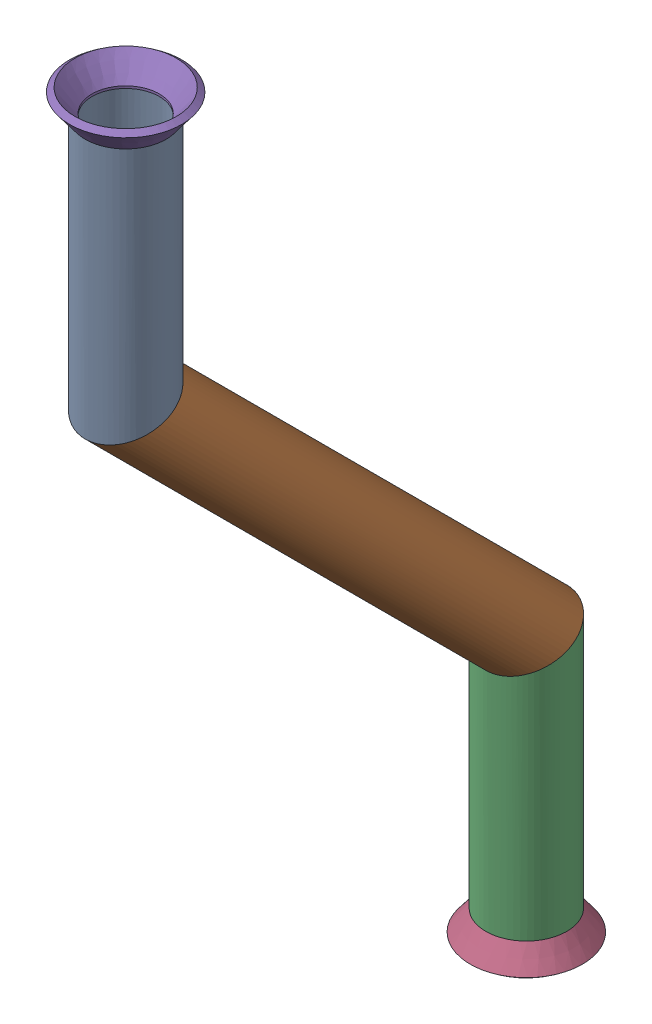
SolidWorks assembly pipe 53, configuration Default. Lengths in mm.
Overall size (17.59 146.84 80.46).
3 component instances, 2 part files, 4 mates.
Components (placement in the parent):
- Part2-1: Part2 [Default<As Machined>] at origin size (12.7 139.06 75.56)
- Flared pipe end - .5 inch-1: Flared pipe end - .5 inch [Default<As Machined>] at (0 -189.578 244.7365) x (1 0 -0.00017) z (0 -1 0) size (17.59 17.59 3.89)
- Flared pipe end - .5 inch-2: Flared pipe end - .5 inch [Default<As Machined>] at (0 -50.5162 307.5983) x (1 0 0.00017) z (0 1 0) size (17.59 17.59 3.89)
Mates (geometry in assembly coordinates):
- Coincident1029: coincident: plane of Part2-1 through (0 -189.578 244.7365) normal (0 -1 0); plane of Flared pipe end - .5 inch-1 through (0.0009 -189.578 250.0197) normal (0 1 0)
- Concentric657: concentric: circle of Part2-1; circle of Flared pipe end - .5 inch-1
- Coincident1027: coincident: plane of Part2-1 through (0 -50.5162 307.5983) normal (0 1 0); plane of Flared pipe end - .5 inch-2 through (0.0009 -50.5162 302.3151) normal (0 -1 0)
- Concentric656: concentric: circle of Part2-1; circle of Flared pipe end - .5 inch-2
